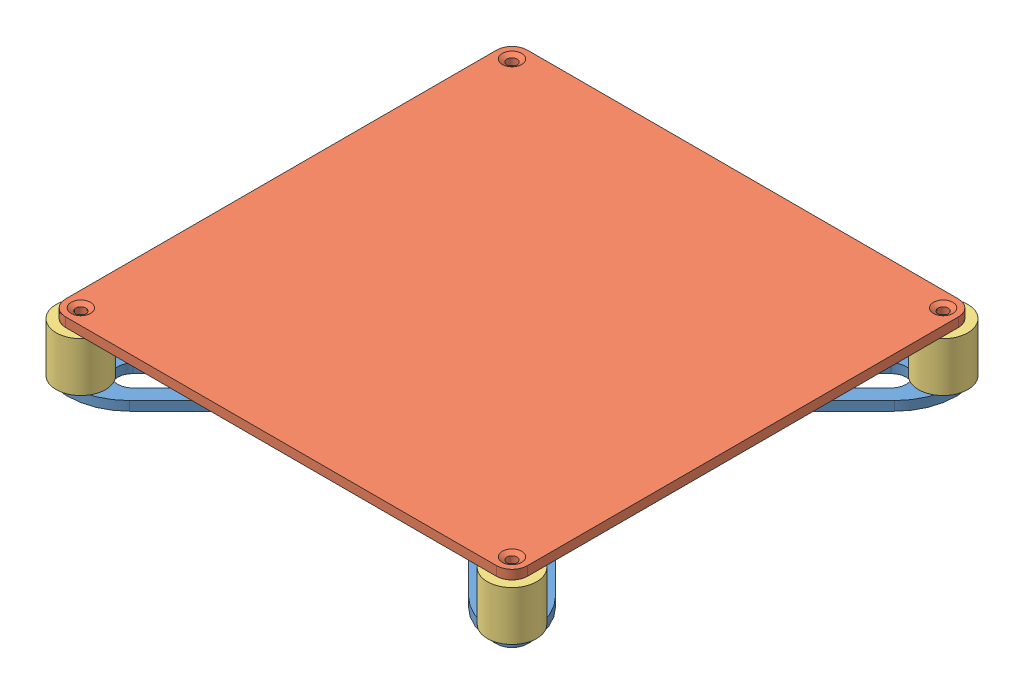
SolidWorks assembly Bed_assemply, configuration Default. Lengths in mm.
Overall size (156 32 156).
7 component instances, 4 part files, 7 mates.
Components (placement in the parent):
- Bed_mount-1: Bed_mount [Default] at origin size (150 3 150)
- Bed_plate-1: Bed_plate [Default] at (0 19 0) size (150 3 150)
- Solid_silicone_spacer-1: Solid_silicone_spacer [Default] at (-70 3 70) size (16 16 16)
- Solid_silicone_spacer-5: Solid_silicone_spacer [Default] at (70 3 70) size (16 16 16)
- Solid_silicone_spacer-6: Solid_silicone_spacer [Default] at (-70 3 -70) size (16 16 16)
- Solid_silicone_spacer-7: Solid_silicone_spacer [Default] at (70 3 -70) size (16 16 16)
- MGN12H-1: MGN12H [Default] at (0 -10 0) x (1 0 0) z (0 1 0) size (27 45.4 10)
Mates (geometry in assembly coordinates):
- Concentric5: concentric: circle of Bed_mount-1; circle of Solid_silicone_spacer-1
- Coincident6: coincident: plane of Bed_mount-1 through (0 3 0) normal (0 1 0); plane of Solid_silicone_spacer-1 through (-70 3 70) normal (0 -1 0)
- Concentric6: concentric: circle of Bed_plate-1; circle of Solid_silicone_spacer-1
- Coincident7: coincident: plane of Bed_plate-1 through (0 19 0) normal (0 -1 0); plane of Solid_silicone_spacer-1 through (-70 19 70) normal (0 1 0)
- Concentric7: concentric: circle of Bed_mount-1; circle of MGN12H-1
- Concentric8: concentric: circle of Bed_mount-1; circle of MGN12H-1
- Coincident8: coincident: plane of Bed_mount-1 through (0 0 0) normal (0 -1 0); plane of MGN12H-1 through (0 0 0) normal (0 1 0)
